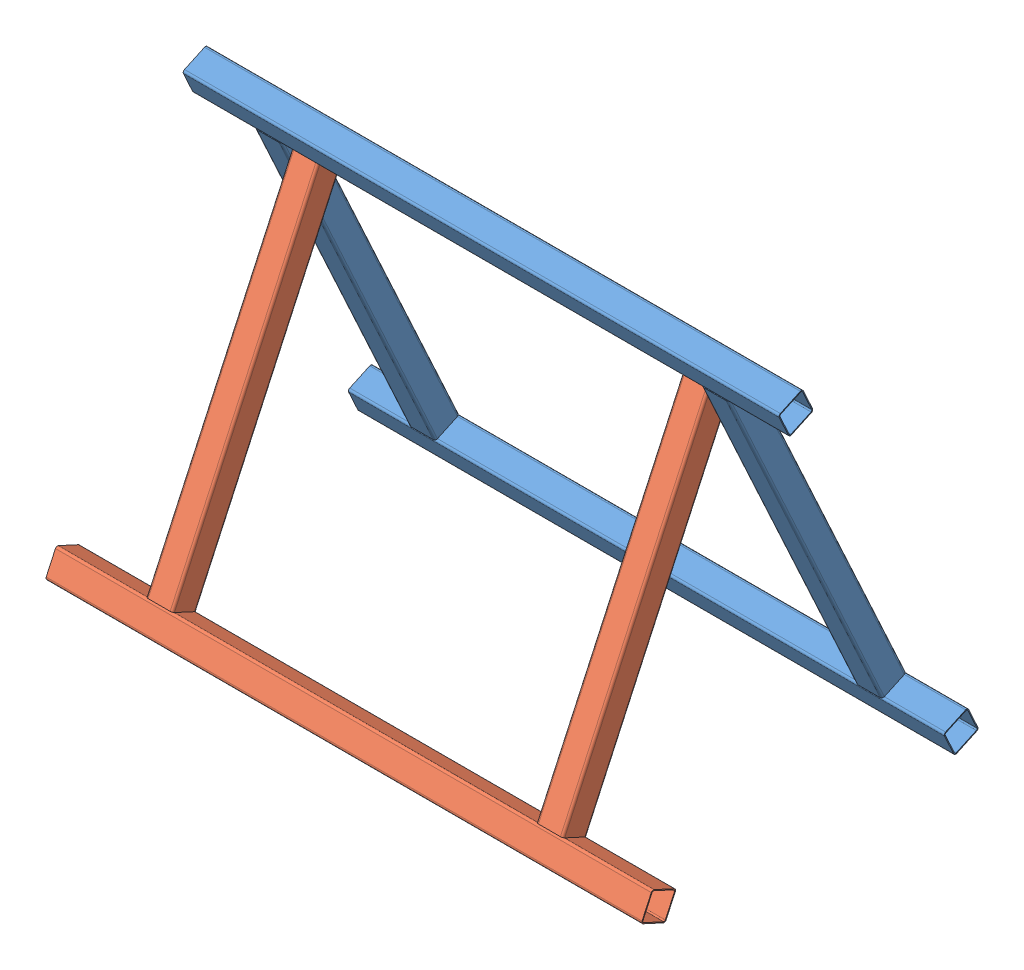
SolidWorks assembly Sawhorse, configuration Default. Lengths in mm.
Overall size (800 582.29 453.3).
2 component instances, 2 part files, 6 mates.
Components (placement in the parent):
- SawhorseOuter-1: SawhorseOuter [Default<As Machined>] x (1 0 0) z (0 -0.418625 0.908159) size (800 595.55 35.6)
- SawhorseInner-1: SawhorseInner [Default<As Machined>] at (0 0 406.0667) x (1 0 0) z (0 0.418625 0.908159) size (800 624.77 35.6)
Mates (geometry in assembly coordinates):
- Coincident1: coincident: point of SawhorseOuter-1; point of assembly
- Coincident2: coincident: line of SawhorseOuter-1 through (-400 0 0) axis (1 0 0); plane of assembly
- Perpendicular1: perpendicular: line of SawhorseOuter-1 through (-400 0 0) axis (1 0 0); plane of assembly
- Concentric1: concentric aligned: cylinder of SawhorseOuter-1 through (-400 440.4571 203.0334) axis (1 0 0) radius 5; cylinder of SawhorseInner-1 through (-400 440.4571 203.0334) axis (1 0 0) radius 5
- Coincident4: coincident aligned: plane of SawhorseInner-1; plane of assembly through (0 0 0) normal (1 0 0)
- Coincident5: coincident: line of SawhorseInner-1 through (-400 0 406.0667) axis (1 0 0); plane of assembly
